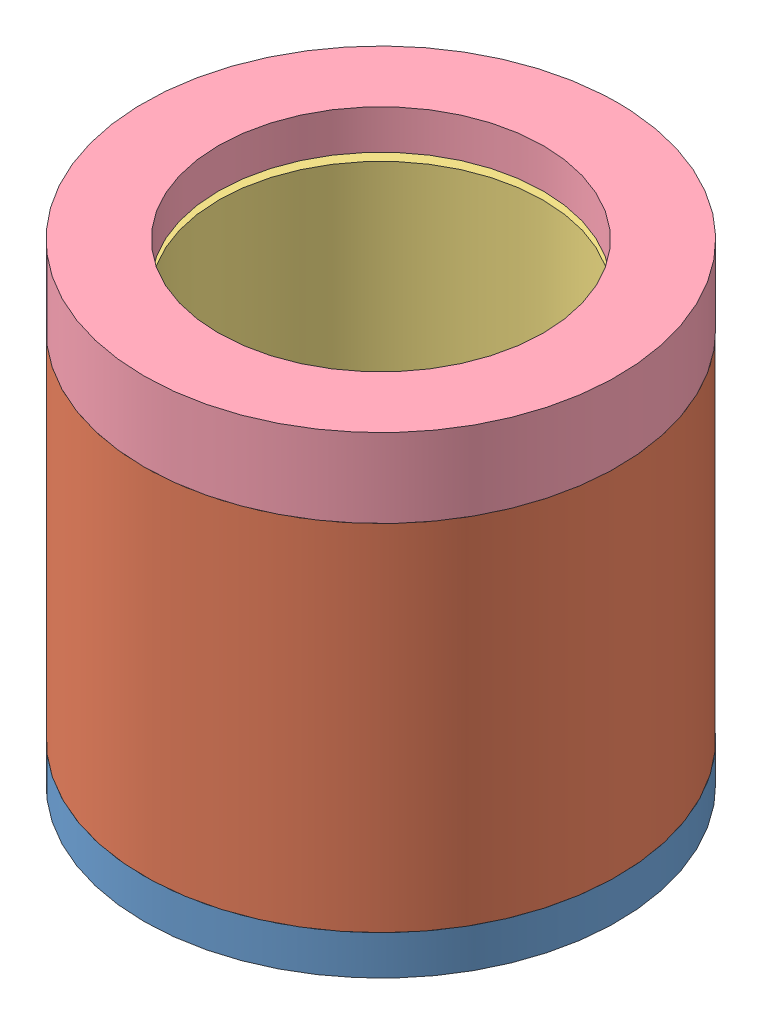
SolidWorks assembly Speaker Housing, configuration Default. Lengths in mm.
Overall size (71.54 60 71.54).
4 component instances, 4 part files, 7 mates.
Components (placement in the parent):
- Speaker Base-1: Speaker Base [Default] at (-9.2176 -9.4786 43.4319) size (60.15 10 60.15)
- Speaker Holder-1: Speaker Holder [Default] at (-9.2176 -4.4786 43.4319) x (0.97723 0 0.212183) z (-0.212183 0 0.97723) size (60.15 45 60.15)
- Electrode Holder-1: Electrode Holder [Default] at (-9.2176 0.5214 43.4319) size (50.55 45 50.55)
- Electrode Cap-1: Electrode Cap [Default] at (-9.2176 50.5214 43.4319) x (0 -1 0) z (0 0 1) size (10 60.15 60.15)
Mates (geometry in assembly coordinates):
- Concentric1: concentric anti-aligned: cylinder of Speaker Base-1 through (-9.2176 -4.9786 43.4319) axis (0 1 0) radius 25.775; cylinder of Speaker Holder-1 through (-9.2176 40.5214 43.4319) axis (0 -1 0) radius 25.775
- Coincident4: coincident anti-aligned: plane of Speaker Base-1 through (-39.2926 -4.4786 43.4319) normal (0 1 0); plane of Speaker Holder-1 through (-9.2176 -4.4786 43.4319) normal (0 -1 0)
- Distance1: distance = 0 mm anti-aligned: plane of Speaker Base-1 through (-34.9926 0.5214 43.4319) normal (0 1 0); plane of Electrode Holder-1 through (-9.2176 0.5214 43.4319) normal (0 -1 0)
- Concentric3: concentric anti-aligned: cylinder of Speaker Base-1 through (-9.2176 0.5214 19.8069) axis (0 -1 0) radius 0.5; cylinder of Electrode Holder-1 through (-9.2176 -1.9786 19.8069) axis (0 1 0) radius 0.5
- Concentric4: concentric aligned: cylinder of Speaker Holder-1 through (-9.2176 40.5214 43.4319) axis (0 -1 0) radius 25.775; cylinder of Electrode Holder-1 through (-9.2176 45.5214 43.4319) axis (0 -1 0) radius 25.275
- Concentric5: concentric anti-aligned: cylinder of Electrode Holder-1 through (-9.2176 45.5214 43.4319) axis (0 -1 0) radius 25.275; cylinder of Electrode Cap-1 through (-9.2176 40.5214 43.4319) axis (0 1 0) radius 20.625
- Coincident5: coincident anti-aligned: plane of Speaker Holder-1 through (-9.2176 40.5214 43.4319) normal (0 1 0); plane of Electrode Cap-1 through (-9.2176 40.5214 43.4319) normal (0 -1 0)
